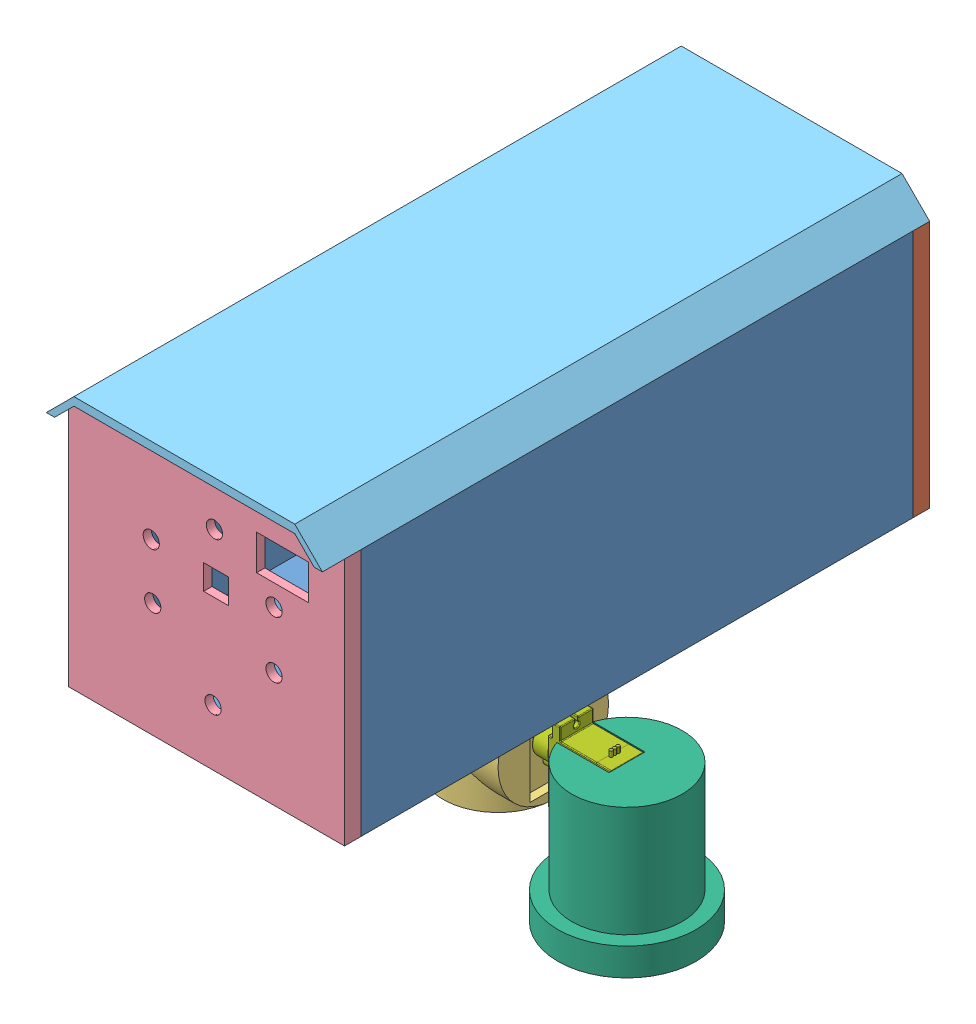
SolidWorks assembly Esamblaje camara, configuration Predeterminado. Lengths in mm.
Overall size (127.69 172.22 220).
9 component instances, 8 part files, 19 mates.
Components (placement in the parent):
- cuerpo camara-1: cuerpo camara [Predeterminado] at (-17.478 -7.7533 -103) size (100 90 206)
- Tapa Trasera-1: Tapa Trasera [Predeterminado] at (-17.478 34.2467 -106) size (100 97 6)
- Pieza2^Esamblaje camara-1: Pieza2^Esamblaje camara [Predeterminado] at origin (virtual)
- pieza de rotacion-1: pieza de rotacion [Predeterminado] at (-14.2904 -60.7533 3.5357) size (40 50 40)
- tapa delantera-1: tapa delantera [Predeterminado] at (-21.7391 16.258 103.1563) size (100 97 6)
- tapa superior-1: tapa superior [Predeterminado] at (-17.478 79.2467 -106) size (100 10 220)
- Base motor-1: Base motor [Predeterminado] at (35.2096 -82.9715 6.3357) x (-1 0 0) z (0 0 -1) size (50 50 50)
- Servo-MG90S[1]-1: Servo-MG90S[1] [Default] at (35.2096 -44.4715 6.0357) x (0 1 0) z (0 0 1) size (32.2 32.5 12.4)
- Servo-MG90S[1]-2: Servo-MG90S[1] [Default] at (-17.1038 18.2467 -0.4002) x (0 0 -1) z (-1 0 0) size (32.2 32.5 12.4)
Mates (geometry in assembly coordinates):
- Coincidente15: coincident anti-aligned: plane of cuerpo camara-1 through (-17.478 -7.7533 100) normal (0 0 1); plane of tapa delantera-1 through (-21.7391 16.258 100) normal (0 0 -1)
- Coincidente16: coincident aligned: plane of cuerpo camara-1 through (32.522 -10.7533 0) normal (0 -1 0); plane of tapa delantera-1 through (-67.478 -10.7533 106) normal (0 -1 0)
- Coincidente17: coincident aligned: plane of cuerpo camara-1 through (32.522 79.2467 0) normal (1 0 0); plane of tapa delantera-1 through (32.522 79.2467 106) normal (1 0 0)
- Coincidente19: coincident anti-aligned: plane of cuerpo camara-1 through (32.522 -10.7533 0) normal (0 -1 0); plane of pieza de rotacion-1 through (-14.2904 -10.7533 3.5357) normal (0 1 0)
- Coincidente23: coincident anti-aligned: plane of cuerpo camara-1 through (-17.478 -7.7533 -100) normal (0 0 -1); plane of Tapa Trasera-1 through (-17.478 34.2467 -100) normal (0 0 1)
- Coincidente24: coincident aligned: plane of cuerpo camara-1 through (32.522 79.2467 0) normal (1 0 0); plane of Tapa Trasera-1 through (32.522 -10.7533 -103) normal (1 0 0)
- Coincidente25: coincident aligned: plane of cuerpo camara-1 through (32.522 -10.7533 0) normal (0 -1 0); plane of Tapa Trasera-1 through (-67.478 -10.7533 -103) normal (0 -1 0)
- Coincidente26: coincident anti-aligned: plane of tapa delantera-1 through (-64.478 79.2467 106) normal (0 1 0); plane of tapa superior-1 through (-64.478 79.2467 114) normal (0 -1 0)
- Coincidente27: coincident aligned: plane of Tapa Trasera-1 through (-17.478 34.2467 -106) normal (0 0 -1); plane of tapa superior-1 through (-17.478 79.2467 -106) normal (0 0 -1)
- Coincidente28: coincident anti-aligned: plane of cuerpo camara-1 through (26.522 79.2467 0) normal (0 1 0); plane of tapa superior-1 through (29.522 79.2467 114) normal (0 -1 0)
- Coincidente30: coincident anti-aligned: line of Tapa Trasera-1 through (29.522 79.2467 -106) axis (-0.707107 0.707107 0); line of tapa superior-1 through (22.522 86.2467 -106) axis (0.707107 -0.707107 0)
- Coincidente43: coincident anti-aligned: plane of Base motor-1 through (-4.7904 -55.9715 -0.1643) normal (0 1 0); plane of Servo-MG90S[1]-1 through (16.7096 -55.9715 12.0357) normal (0 -1 0)
- Coincidente44: coincident anti-aligned: plane of Base motor-1 through (35.2096 -82.9715 6.3357) normal (-1 0 0); plane of Servo-MG90S[1]-1 through (35.2096 -44.4715 6.0357) normal (1 0 0)
- Coincidente45: coincident anti-aligned: plane of Base motor-1 through (-4.7904 -32.9715 -0.1643) normal (0 0 1); plane of Servo-MG90S[1]-1 through (35.2096 -44.4715 -0.1643) normal (0 0 -1)
- Coincidente46: coincident anti-aligned: plane of pieza de rotacion-1 through (2.7096 -60.7533 3.5357) normal (1 0 0); plane of Servo-MG90S[1]-1 through (2.7096 -39.2215 6.0357) normal (-1 0 0)
- Coincidente48: coincident anti-aligned: plane of pieza de rotacion-1 through (2.7096 -24.0033 12.0357) normal (0 0 -1); plane of Servo-MG90S[1]-1 through (16.7096 -55.9715 12.0357) normal (0 0 1)
- Coincidente50: coincident anti-aligned: plane of cuerpo camara-1 through (-61.478 -4.7533 0) normal (0 1 0); plane of Servo-MG90S[1]-2 through (-17.1038 -4.7533 -0.4002) normal (0 -1 0)
- Paralelo5: parallel aligned: line of cuerpo camara-1 through (-11.228 -4.7533 11.5) axis (0 0 -1); line of Servo-MG90S[1]-2 through (-11.1038 -4.4533 10.5498) axis (0 0 -1)
- Paralelo7: parallel anti-aligned: plane of pieza de rotacion-1 through (-14.2904 -13.7533 3.5357) normal (0 1 0); plane of Servo-MG90S[1]-2 through (-17.1038 -14.2533 -5.6502) normal (0 -1 0)
